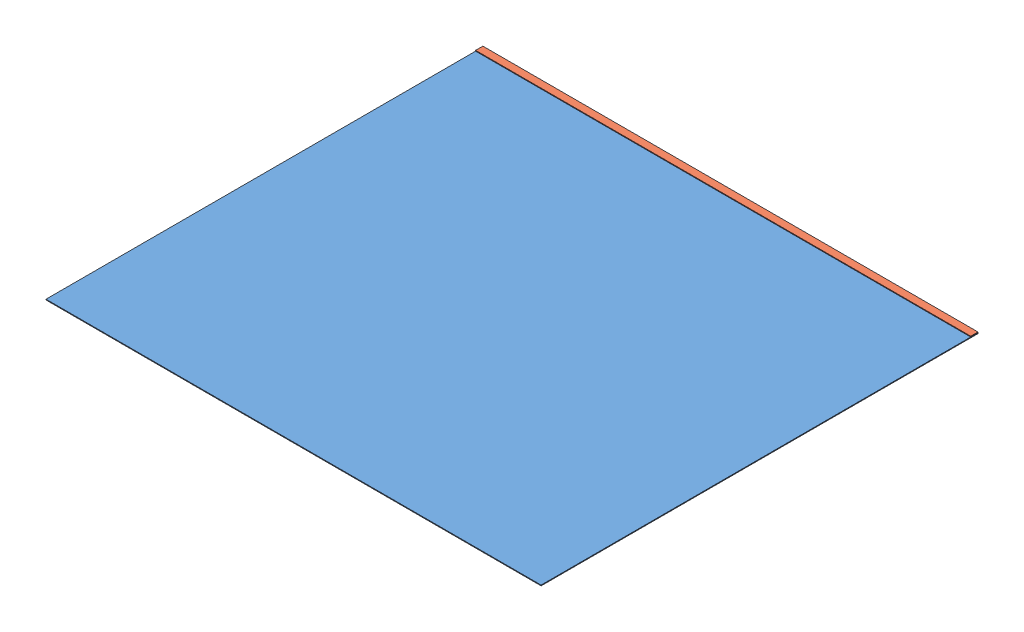
SolidWorks assembly GE-19231, configuration Default. Lengths in mm.
Overall size (1727.2 5.08 1524).
2 component instances, 2 part files, 3 mates.
Components (placement in the parent):
- Fabric-1: Fabric [Default] at (730.3903 806.1408 1344.3845) size (1727.2 2.54 1524)
- LopForSandstorm-1: LopForSandstorm [Default] at (730.3903 808.6808 595.0845) size (1727.2 2.54 25.4)
Mates (geometry in assembly coordinates):
- Coincident2: coincident: plane of Fabric-1 through (730.3903 808.6808 1344.3845) normal (0 1 0); plane of ? through (730.3903 808.6808 630.7126) normal (0 -1 0)
- Coincident3: coincident: plane of Fabric-1 through (1593.9903 808.6808 2106.3845) normal (1 0 0); plane of ? through (1593.9903 811.2208 643.4126) normal (1 0 0)
- Coincident4: coincident: plane of Fabric-1 through (-133.2097 808.6808 582.3845) normal (0 0 -1); plane of LopForSandstorm-1 through (-133.2097 811.2208 582.3845) normal (0 0 -1)
